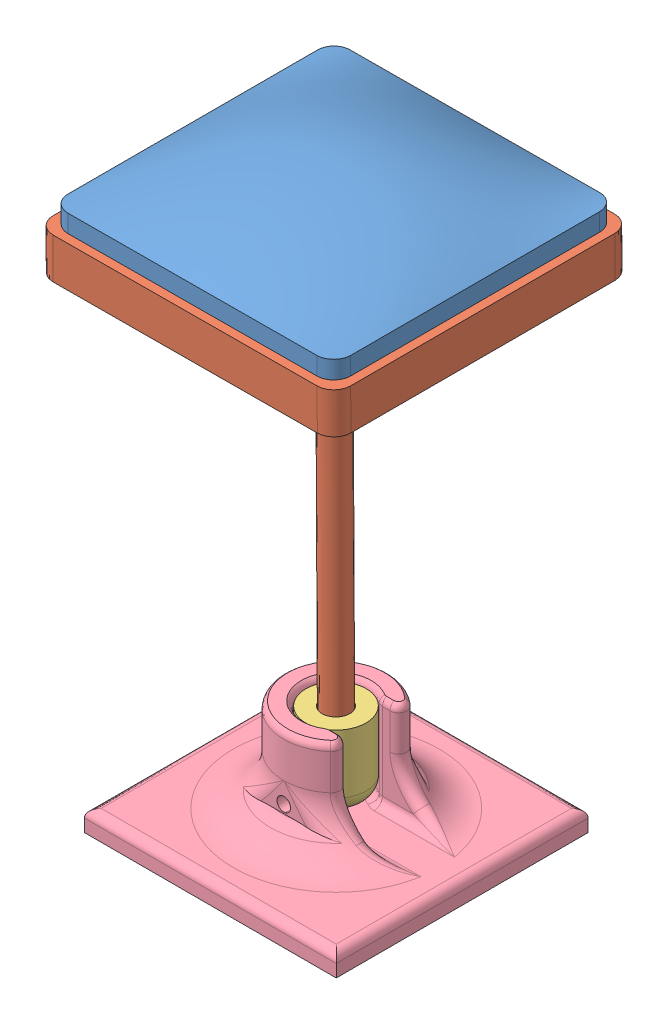
SolidWorks assembly GPS Mount, configuration Default. Lengths in mm.
Overall size (45.37 92.42 45.02).
4 component instances, 4 part files, 19 mates.
Components (placement in the parent):
- 3DR_GPS-1: 3DR_GPS [Default] at (-0.3332 -0.8835 0) x (0.999988 0.004985 0) z (0 0 1) size (42.74 17.78 42.74)
- 3DR_GPS_Mast-1: 3DR_GPS_Mast [Default] at (0.1524 -66.452 0.1588) x (0.999988 0.004985 0) z (0 0 1) size (45.02 70.51 45.02)
- Pin Coupler^GPS Mount-1: Pin Coupler^GPS Mount [Default] at (0.1524 -66.452 0.1588) x (-0.999988 -0.004985 0) z (0.004985 -0.999988 0) size (9.07 9.07 11.43) (virtual)
- GPS Base^GPS Mount-1: GPS Base^GPS Mount [Default] at (0.1588 -70.6501 0.1588) x (-1 0 0) z (0 -1 0) size (38.1 38.1 17.26) (virtual)
Mates (geometry in assembly coordinates):
- Coincident1: coincident anti-aligned: plane of 3DR_GPS-1 through (-0.3332 -0.8835 0) normal (0.004985 -0.999988 0); plane of 3DR_GPS_Mast-1 through (-0.1744 -0.8827 0.1588) normal (-0.004985 0.999988 0)
- Coincident2: coincident anti-aligned: plane of 3DR_GPS-1 through (-21.7387 6.6299 21.3678) normal (0 0 1); plane of 3DR_GPS_Mast-1 through (-0.1991 4.0575 21.3678) normal (0 0 -1)
- Coincident3: coincident anti-aligned: plane of 3DR_GPS-1 through (20.9963 6.8429 21.3678) normal (0.999988 0.004985 0); plane of 3DR_GPS_Mast-1 through (21.0097 4.1632 0.1588) normal (-0.999988 -0.004985 0)
- Coincident4: coincident aligned: plane of 3DR_GPS-1 through (-0.3332 -0.8835 0) normal (0 0 1); plane of assembly through (0 0 0) normal (0 0 1)
- Coincident5: coincident aligned: plane of 3DR_GPS-1 through (0 0 0) normal (0 1 0); plane of assembly through (0 0 0) normal (0 1 0)
- Coincident6: coincident aligned: plane of 3DR_GPS-1 through (0 0 0) normal (1 0 0); plane of assembly through (0 0 0) normal (1 0 0)
- InPlace1: in place: plane of ? through (0.1588 -65.5701 0.1588) normal (0 -1 0); plane of ? through (0 -65.5701 0) normal (0 -1 0); moOrthogonalPlaneRef_w of ? through (0.1588 -65.5701 0.1588) normal (0 -1 0); unknown of ?; plane of ? through (0.1588 -65.5701 0.1588) normal (0 -1 0); line of ? through (-55 0 -65.5701) axis (0 -1 0); unknown of ?; unknown of ?
- Coincident7: coincident aligned: plane of 3DR_GPS_Mast-1; plane of Pin Coupler^GPS Mount-1
- Coincident8: coincident aligned: moOrthogonalPlaneRef_w of 3DR_GPS_Mast-1 through (0.2437 -65.5796 0.1588) normal (0 0 -1); plane of Pin Coupler^GPS Mount-1
- Coincident9: coincident anti-aligned: moOrthogonalPlaneRef_w of 3DR_GPS_Mast-1; plane of Pin Coupler^GPS Mount-1
- InPlace2: in place: plane of ? through (0.1588 -70.6501 0.1588) normal (0 -1 0); plane of ? through (0 -70.6501 0) normal (0 -1 0); plane of ? through (0.1588 -70.6501 0.1588) normal (0 -1 0); unknown of ?; plane of ? through (0.1588 -70.6501 0.1588) normal (0 -1 0); line of ? through (-55 0 -70.6501) axis (0 -1 0); unknown of ?; unknown of GPS Base^GPS Mount-1
- Coincident10: coincident aligned: plane of Pin Coupler^GPS Mount-1; plane of GPS Base^GPS Mount-1
- Coincident11: coincident aligned: moOrthogonalPlaneRef_w of Pin Coupler^GPS Mount-1 through (0.1588 -70.6501 0.1588) normal (0 0 -1); plane of GPS Base^GPS Mount-1
- Coincident12: coincident anti-aligned: moOrthogonalPlaneRef_w of Pin Coupler^GPS Mount-1 through (0.1588 -70.6501 0.1588) normal (1 0 0); plane of GPS Base^GPS Mount-1
- Concentric3: concentric aligned: cylinder of 3DR_GPS_Mast-1 through (-0.1611 -3.5624 0.1588) axis (0.004985 -0.999988 0) radius 1.9939; cylinder of Pin Coupler^GPS Mount-1 through (0.1144 -58.8321 0.1588) axis (0.004985 -0.999988 0) radius 2.0892
- Coincident7: coincident anti-aligned: plane of 3DR_GPS_Mast-1 through (0.1524 -66.452 0.1588) normal (0.004985 -0.999988 0); plane of Pin Coupler^GPS Mount-1 through (0.1524 -66.452 0.1588) normal (-0.004985 0.999988 0)
- Parallel2: parallel anti-aligned: plane of Pin Coupler^GPS Mount-1; plane of assembly through (0 0 0) normal (0 0 1)
- Concentric5: concentric anti-aligned: cylinder of Pin Coupler^GPS Mount-1 through (0.1588 -58.832 0.1588) axis (0 -1 0) radius 4.5339; cylinder of GPS Base^GPS Mount-1 through (0.1588 -75.4126 0.1588) axis (0 1 0) radius 4.7244
- Concentric6: concentric aligned: cylinder of Pin Coupler^GPS Mount-1 through (0.1588 -67.722 -4.3752) axis (0 0 -1) radius 1.0287; cylinder of GPS Base^GPS Mount-1 through (0.1588 -67.722 -7.7788) axis (0 0 -1) radius 1.0287
